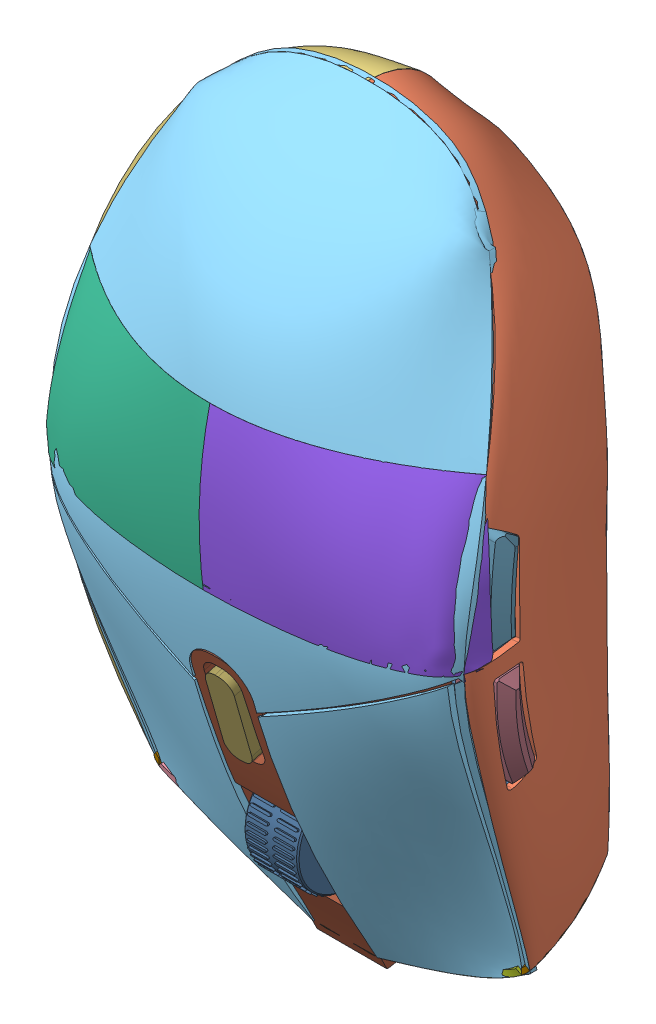
SolidWorks assembly G102, configuration Varsayılan. Lengths in mm.
Overall size (75.71 117.37 44.46).
15 component instances, 14 part files, 0 mates.
Components (placement in the parent):
- (7) G102.step-1: (7) G102.step [Default] at origin size (75.71 117.37 44.46)
  - BottomPart.step-1: BottomPart.step [Default] at origin size (53.24 101.9 4.68)
  - RightSidePart.step-1: RightSidePart.step [Default] at origin size (34.08 104.55 29.08)
  - LeftSidePart.step-1: LeftSidePart.step [Default] at origin size (34.14 104.55 29.07)
  - TopLeftFrontPart.step-1: TopLeftFrontPart.step [Varsayılan] at origin size (23.7 11.54 4.78)
  - TopPart.step-1: TopPart.step [Varsayılan] at origin size (72.05 116.99 33.29)
  - TopMidLeftPart.step-1: TopMidLeftPart.step [Varsayılan] at origin size (42.73 30.52 18.36)
  - TopRightFrontPart.step-1: TopRightFrontPart.step [Varsayılan] at origin size (23.7 11.54 4.78)
  - TopMidRightPart.step-1: TopMidRightPart.step [Varsayılan] at origin size (42.73 30.52 18.51)
  - FrontPart.step-1: FrontPart.step [Varsayılan] at origin size (59.94 20.08 16.09)
  - Mouse Wheel.step-1: Mouse Wheel.step [Varsayılan] at (0 -38 19) size (8.5 16.6 16.6)
  - MouseWheelBase.step-1: MouseWheelBase.step [Varsayılan] at origin size (11 50.63 31.75)
  - MiddleButton.step-1: MiddleButton.step [Varsayılan] at origin size (4.5 15.66 11.55)
  - M4.step-1: M4.step [Varsayılan] at (31.25 -7 21.75) size (8 15.99 6.4)
  - M5.step-1: M5.step [Default] at (30.75 11.5 23) size (8 15.71 4.27)
